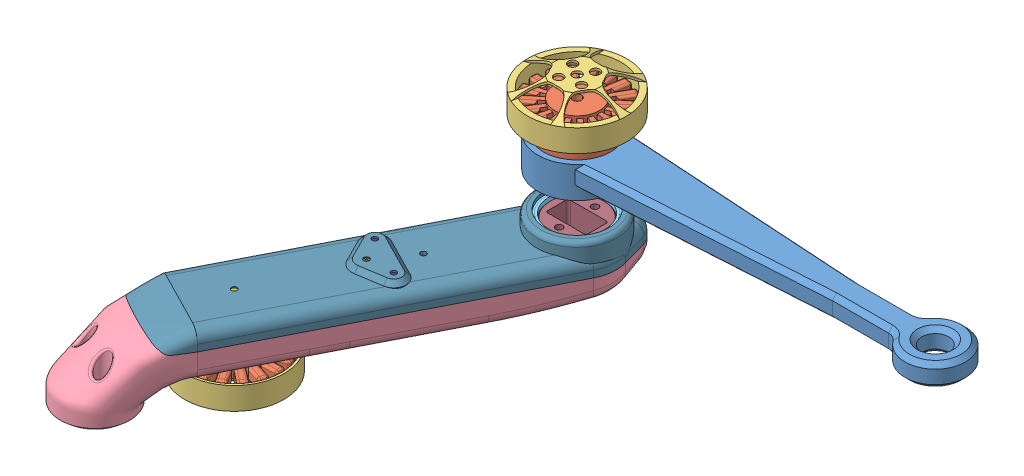
SolidWorks assembly Assem3, configuration Default. Lengths in mm.
Overall size (281.12 97.37 204.93).
32 component instances, 17 part files, 4 mates.
Components (placement in the parent):
- lower leg v2-1: lower leg v2 [Default] at (60.4393 126.2385 190.5491) x (1 0 0) z (0 0 -1) size (191 20 35)
- T-motor 4004 kv300-1: T-motor 4004 kv300 [Default] at (-33.7284 114.1082 158.0883) size (60.94 23.74 60.94)
  - motor rotor-1: motor rotor [Default] at (14.1676 19.6303 32.4608) size (40 13.5 39.72)
  - motor stator-1: motor stator [Default] at (14.1676 19.6303 32.4608) x (0.854442 0 0.519546) z (0 1 0) size (44.35 44.35 16.24)
- actuator core assembly-1: actuator core assembly [Default] at (-42.4958 -16.241 80.0145) x (0.89053 0 0.454924) z (-0.454924 0 0.89053) size (62.38 43.94 198.25)
  - upper limb base-1: upper limb base [Default] at (70.7092 92.7911 149.0007) size (42.52 37.51 198.25)
    - upper leg module shell base-1: upper leg module shell base [Default] x (-1 0 0) z (0 0 -1) size (37.02 37.51 198.25)
    - bearing 32x25x4mm-1: bearing 32x25x4mm [Default] at (0 0.5 -61) x (0.90658 0 0.422034) z (-0.422034 0 0.90658) size (32 4 32)
    - bearing 8mm x 3mm x 3mm-1: bearing 8mm x 3mm x 3mm [Default] at (0 -1.5 8.9) x (1 0 0) z (0 -1 0) size (7.96 7.96 3)
  - motor rotor-1: motor rotor [Default] at (70.7092 85.0911 201.8007) x (0 0 -1) z (-1 0 0) size (40 13.5 39.72)
  - motor assembly-2: motor assembly [Default] at (70.7092 72.4911 201.8007) x (-0.761097 0 -0.648639) z (-0.648639 0 0.761097) size (16.67 33.4 16.67)
    - motor shaft-1: motor shaft [Default] x (1 0 0) z (0 -1 0) size (3.99 3.99 33.4)
    - motor pulley-1: motor pulley [Default] at (0 -20.1 0) x (1 0 0) z (0 -1 0) size (8.98 9.1 6.7)
    - encoder wheel mount-1: encoder wheel mount [Default] at (0 -28.3 0) x (-0.562764 0 0.826618) z (-0.826618 0 -0.562764) size (12 5.96 12)
  - motor stator-1: motor stator [Default] at (70.7092 85.0911 201.8007) x (0.629554 0 -0.776957) z (0 -1 0) size (44.35 44.35 16.24)
  - B18.6.7M - M3 x 0.5 x 5 Type I Cross Recessed FHMS --5S-1: B18.6.7M - M3 x 0.5 x 5 Type I Cross Recessed FHMS --5S [B18.6.7M - M3 x 0.5 x 5 Type I Cross Recessed FHMS --5S] at (83.2092 94.5911 201.8007) x (0 -1 0) z (-0.166423 0 0.986054) size (5 5.5 5.5)
  - B18.6.7M - M3 x 0.5 x 5 Type I Cross Recessed FHMS --5S-2: B18.6.7M - M3 x 0.5 x 5 Type I Cross Recessed FHMS --5S [B18.6.7M - M3 x 0.5 x 5 Type I Cross Recessed FHMS --5S] at (70.7092 94.5911 214.3007) x (0 -1 0) z (0.029806 0 0.999556) size (5 5.5 5.5)
  - B18.6.7M - M3 x 0.5 x 5 Type I Cross Recessed FHMS --5S-3: B18.6.7M - M3 x 0.5 x 5 Type I Cross Recessed FHMS --5S [B18.6.7M - M3 x 0.5 x 5 Type I Cross Recessed FHMS --5S] at (58.2092 94.5911 201.8007) x (0 -1 0) z (0.999629 0 -0.027231) size (5 5.5 5.5)
  - B18.6.7M - M3 x 0.5 x 5 Type I Cross Recessed FHMS --5S-4: B18.6.7M - M3 x 0.5 x 5 Type I Cross Recessed FHMS --5S [B18.6.7M - M3 x 0.5 x 5 Type I Cross Recessed FHMS --5S] at (70.7092 94.5911 189.3007) x (0 -1 0) z (-0.93368 0 0.358107) size (5 5.5 5.5)
  - centre pulley-1: centre pulley [Default] at (66.4357 80.4446 131.9015) x (0.990944 0 0.134278) z (-0.134278 0 0.990944) size (30 19 30)
    - transmission pulley centre-1: transmission pulley centre [Default] at (7.726 11.8465 25.1899) size (30 6.8 30)
    - centre pulley-1: centre pulley [Default] at (7.726 25.3465 25.1899) x (0.694658 0 -0.71934) z (0 -1 0) size (8.98 9.1 19)
  - transmission pulley output-1: transmission pulley output [Default] at (70.7092 97.7911 88.0007) x (-0.454924 0 -0.89053) z (0.89053 0 -0.454924) size (29 16.4 29)
  - upper leg module cover-1: upper leg module cover [Default] at (70.7092 98.7911 142.6299) x (0 0 1) z (-1 0 0) size (170.23 17.96 37.06)
  - bearing 32x25x4mm-1: bearing 32x25x4mm [Default] at (70.7092 107.2911 88.0007) size (32 4 32)
  - bearing 8mm x 3mm x 3mm-1: bearing 8mm x 3mm x 3mm [Default] at (70.7092 107.2911 157.9007) x (1 0 0) z (0 -1 0) size (7.96 7.96 3)
  - transmission belt tension roller-1: transmission belt tension roller [Default] at (60.9592 99.8911 152.0007) x (0.454066 0 0.890968) z (-0.890968 0 0.454066) size (10 4 10)
  - bearing 7mm x 3mm x 3mm-2: bearing 7mm x 3mm x 3mm [Default] at (60.9592 103.8911 152.0007) x (0.030533 0 0.999534) z (0 -1 0) size (7 7 3)
  - transmission belt tension roller-2: transmission belt tension roller [Default] at (80.4592 99.8911 152.0007) x (0.177081 0 -0.984196) z (0.984196 0 0.177081) size (10 4 10)
  - bearing 7mm x 3mm x 3mm-3: bearing 7mm x 3mm x 3mm [Default] at (80.4592 103.8911 152.0007) x (0 0 -1) z (0 -1 0) size (7 7 3)
  - flat head screw_am-1: flat head screw_am [B18.6.7M - M3 x 0.5 x 8 Type I Cross Recessed FHMS --8S] at (60.9592 100.0411 152.0007) x (0 1 0) z (0.851744 0 -0.523958) size (8 5.5 5.5)
  - flat head screw_am-2: flat head screw_am [B18.6.7M - M3 x 0.5 x 8 Type I Cross Recessed FHMS --8S] at (80.4592 100.0411 152.0007) x (0 1 0) z (0.851744 0 -0.523958) size (8 5.5 5.5)
Mates (geometry in assembly coordinates):
- Concentric1: concentric anti-aligned: cylinder of T-motor 4004 kv300-1/motor rotor-1 through (-19.5607 126.2385 190.5491) axis (0 1 0) radius 15; cylinder of lower leg v2-1 through (-19.5607 175.736 190.5491) axis (0 -1 0) radius 17.5
- Coincident1: coincident anti-aligned: plane of lower leg v2-1 through (125.5648 126.2385 179.5491) normal (0 1 0); plane of T-motor 4004 kv300-1/motor rotor-1 through (-19.5607 126.2385 190.5491) normal (0 -1 0)
- Coincident2: coincident anti-aligned: plane of lower leg v2-1 through (-27.0607 106.2385 185.5491) normal (0 0 -1); plane of actuator core assembly-1/transmission pulley output-1 through (-10.5607 77.2002 185.5491) normal (0 0 1)
- Coincident3: coincident anti-aligned: plane of lower leg v2-1 through (-28.5607 106.2385 187.0491) normal (-1 0 0); plane of actuator core assembly-1/transmission pulley output-1 through (-28.5607 77.2002 185.5491) normal (1 0 0)
